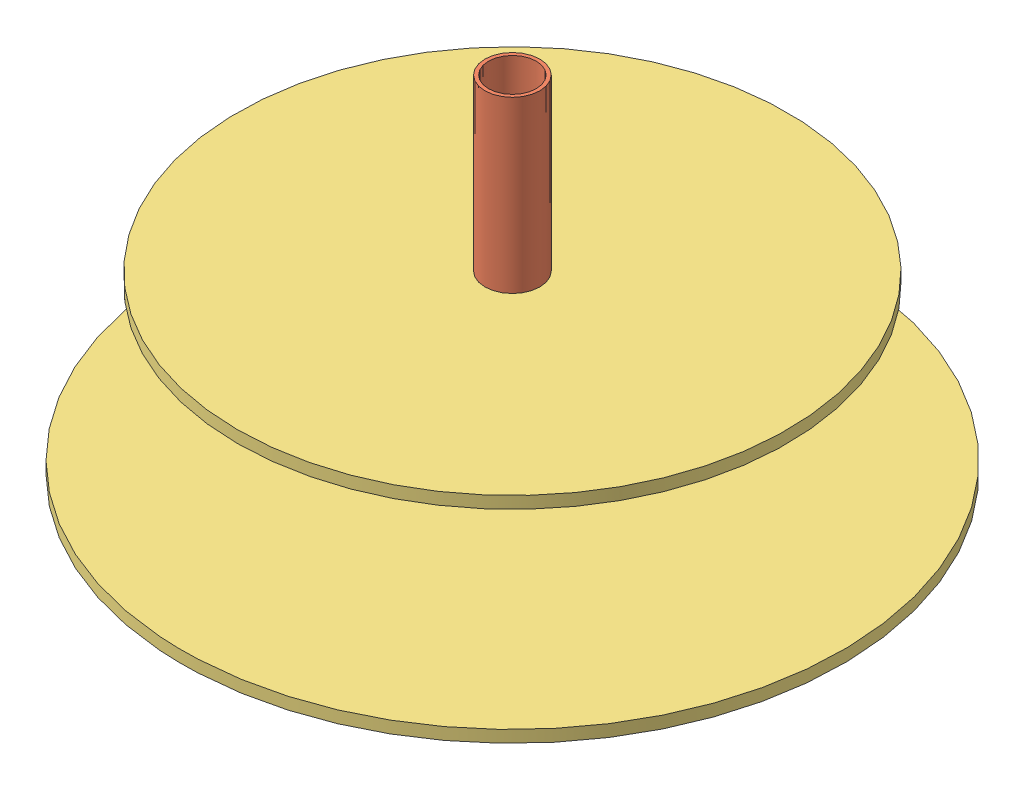
SolidWorks assembly asu, configuration Default. Lengths in mm.
Overall size (231.58 152.4 231.58).
4 component instances, 3 part files, 5 mates.
Components (placement in the parent):
- asu adapter-1: asu adapter [Default] at origin size (16.56 11.43 16.56)
- asu tube-1: asu tube [Default] at origin size (19.05 152.4 19.05)
- asu top shield-1: asu top shield [Default] at (0 32.5889 0) x (0.999914 0 0.013142) z (-0.013142 0 0.999914) size (228.6 4.16 228.6)
- asu top shield-4: asu top shield [smaller] at (0 89.3531 0) size (190.5 4.16 190.5)
Mates (geometry in assembly coordinates):
- Coincident1: coordinate: point of ?
- Coincident4: coincident aligned: plane of asu adapter-1 through (0 0 0) normal (0 -1 0); plane of asu tube-1 through (0 0 0) normal (0 -1 0)
- Concentric1: concentric aligned: cylinder of asu adapter-1 through (0 11.43 0) axis (0 -1 0) radius 8.2804; cylinder of asu tube-1 through (0 152.4 0) axis (0 -1 0) radius 8.2804
- Concentric2: concentric aligned: cylinder of asu tube-1 through (0 152.4 0) axis (0 -1 0) radius 9.525; cylinder of asu top shield-1 through (0 36.7489 0) axis (0 -1 0) radius 9.525
- Concentric5: concentric aligned: cylinder of asu tube-1 through (0 152.4 0) axis (0 -1 0) radius 9.525; cylinder of asu top shield-4 through (0 93.5131 0) axis (0 -1 0) radius 9.525
